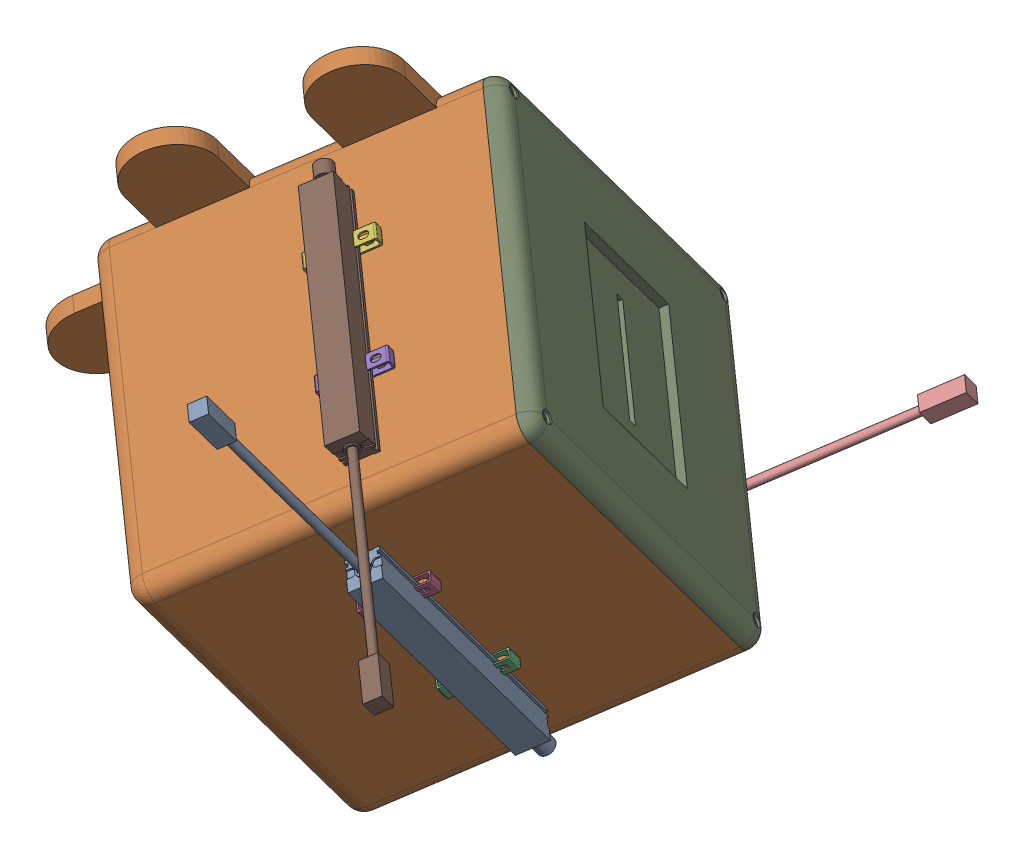
SolidWorks assembly CajaCompleta, configuration Predeterminado. Lengths in mm.
Overall size (364.03 428.6 429.87).
11 component instances, 4 part files, 30 mates.
Components (placement in the parent):
- Sensor-1: Sensor [Predeterminado] at (-9.7857 -175.398 154.3753) x (-0.665785 -0.507971 0.546532) z (-0.153398 0.810013 0.565993) size (17.8 17.82 298.41)
- Servicio-1: Servicio [Predeterminado] at (-86.6429 -170.5093 84.1469) x (-0.730205 0.292992 -0.617216) z (-0.153398 0.810013 0.565993) size (200 250 300)
- soporteSensor-1: soporteSensor [Predeterminado] at (-10.5547 -140.3431 170.4675) x (-0.665785 -0.507971 0.546532) z (-0.153398 0.810013 0.565993) size (37.6 6.1 8.9)
- soporteSensor-2: soporteSensor [Predeterminado] at (-20.9676 -85.3782 208.8785) x (-0.665785 -0.507971 0.546532) z (-0.153398 0.810013 0.565993) size (37.6 6.1 8.9)
- soporteSensor-3: soporteSensor [Predeterminado] at (-91.6649 -13.9921 212.1498) x (0.665785 0.507971 -0.546532) z (0.730205 -0.292992 0.617216) size (37.6 6.1 8.9)
- soporteSensor-4: soporteSensor [Predeterminado] at (-141.2166 5.8903 170.2655) x (0.665785 0.507971 -0.546532) z (0.730205 -0.292992 0.617216) size (37.6 6.1 8.9)
- soporteSensor-5: soporteSensor [Predeterminado] at (-47.3623 -156.5216 74.7747) x (-0.730205 0.292992 -0.617216) z (-0.665785 -0.507971 0.546532) size (37.6 6.1 8.9)
- soporteSensor-6: soporteSensor [Predeterminado] at (-92.5406 -190.9932 111.8639) x (-0.730205 0.292992 -0.617216) z (-0.665785 -0.507971 0.546532) size (37.6 6.1 8.9)
- Servicio_tapa-1: Servicio_tapa [Predeterminado] at (-35.4043 -38.7109 86.093) x (0.153398 -0.810013 -0.565993) z (0.665785 0.507971 -0.546532) size (200 200 10)
- Sensor-2: Sensor [Predeterminado] at (-140.7801 -203.8923 115.6599) x (0.730205 -0.292992 0.617216) z (0.665785 0.507971 -0.546532) size (17.8 17.82 298.41)
- Sensor-3: Sensor [Predeterminado] at (-154.1478 18.341 150.5324) x (0.665785 0.507971 -0.546532) z (0.730205 -0.292992 0.617216) size (17.8 17.82 298.41)
Mates (geometry in assembly coordinates):
- Coincidente1: coincident anti-aligned: plane of Servicio-1 through (22.2765 12.9912 204.4139) normal (0.730205 -0.292992 0.617216); plane of soporteSensor-1 through (-11.9199 -133.134 175.5048) normal (-0.730205 0.292992 -0.617216)
- Concéntrica1: concentric aligned: cylinder of Servicio-1 through (-15.9467 -140.378 176.83) axis (0.730205 -0.292992 0.617216) radius 2; cylinder of soporteSensor-1 through (-9.4479 -142.9857 182.3232) axis (0.730205 -0.292992 0.617216) radius 2
- Coincidente3: coincident anti-aligned: plane of Servicio-1 through (22.2765 12.9912 204.4139) normal (0.730205 -0.292992 0.617216); plane of soporteSensor-2 through (-22.3329 -78.1691 213.9158) normal (-0.730205 0.292992 -0.617216)
- Concéntrica2: concentric aligned: cylinder of Servicio-1 through (-26.375 -85.3321 215.2976) axis (0.730205 -0.292992 0.617216) radius 2; cylinder of soporteSensor-2 through (-19.8762 -87.9397 220.7908) axis (0.730205 -0.292992 0.617216) radius 2
- Coincidente4: coincident anti-aligned: plane of Servicio-1 through (-86.6429 -170.5093 84.1469) normal (0.153398 -0.810013 -0.565993); plane of soporteSensor-6 through (-98.4661 -195.5142 116.728) normal (-0.153398 0.810013 0.565993)
- Coincidente5: coincident anti-aligned: plane of Servicio-1 through (-86.6429 -170.5093 84.1469) normal (0.153398 -0.810013 -0.565993); plane of soporteSensor-5 through (-53.2877 -161.0426 79.6388) normal (-0.153398 0.810013 0.565993)
- Concéntrica3: concentric aligned: cylinder of Servicio-1 through (-55.9039 -149.0202 79.3922) axis (0.153398 -0.810013 -0.565993) radius 2; cylinder of soporteSensor-5 through (-53.0047 -164.3294 68.695) axis (0.153398 -0.810013 -0.565993) radius 2
- Concéntrica4: concentric aligned: cylinder of Servicio-1 through (-101.0822 -183.4918 116.4814) axis (0.153398 -0.810013 -0.565993) radius 2; cylinder of soporteSensor-6 through (-98.183 -198.8011 105.7841) axis (0.153398 -0.810013 -0.565993) radius 2
- Coincidente6: coincident anti-aligned: plane of Servicio-1 through (-117.3225 -8.5067 197.3455) normal (-0.153398 0.810013 0.565993); plane of soporteSensor-3 through (-85.1661 -16.5997 217.643) normal (0.153398 -0.810013 -0.565993)
- Coincidente7: coincident anti-aligned: plane of Servicio-1 through (-117.3225 -8.5067 197.3455) normal (-0.153398 0.810013 0.565993); plane of soporteSensor-4 through (-134.7178 3.2827 175.7587) normal (0.153398 -0.810013 -0.565993)
- Coincidente9: coincident anti-aligned: plane of Sensor-1 through (-31.8014 -59.1449 235.6066) normal (-0.730205 0.292992 -0.617216); plane of soporteSensor-2 through (-20.3104 -85.6419 209.434) normal (0.730205 -0.292992 0.617216)
- Coincidente10: coincident anti-aligned: plane of Servicio-1 through (22.2765 12.9912 204.4139) normal (0.665785 0.507971 -0.546532); plane of Servicio_tapa-1 through (-35.4043 -38.7109 86.093) normal (-0.665785 -0.507971 0.546532)
- Coincidente11: coincident aligned: line of Servicio-1 through (-42.2658 -95.6948 229.1782) axis (-0.665785 -0.507971 0.546532); line of soporteSensor-2 through (-42.2658 -95.6948 229.1782) axis (-0.665785 -0.507971 0.546532)
- Coincidente12: coincident aligned: line of Servicio-1 through (-31.8595 -150.6648 190.7727) axis (-0.665785 -0.507971 0.546532); line of soporteSensor-1 through (-31.8529 -150.6598 190.7672) axis (-0.665785 -0.507971 0.546532)
- Coincidente13: coincident anti-aligned: circle of Servicio-1; circle of Servicio_tapa-1
- Coincidente14: coincident anti-aligned: circle of Servicio-1; circle of Servicio_tapa-1
- Coincidente21: coincident anti-aligned: circle of Servicio-1; circle of soporteSensor-5
- Coincidente41: coincident anti-aligned: line of Servicio-1 through (-116.4891 -183.3218 94.3943) axis (-0.730205 0.292992 -0.617216); line of soporteSensor-6 through (-117.5826 -182.883 93.47) axis (0.730205 -0.292992 0.617216)
- Coincidente44: coincident anti-aligned: plane of Sensor-1 through (-31.8014 -59.1449 235.6066) normal (-0.730205 0.292992 -0.617216); plane of soporteSensor-1 through (-9.8975 -140.6068 171.023) normal (0.730205 -0.292992 0.617216)
- Coincidente45: coincident anti-aligned: plane of Sensor-1 through (-43.6524 -68.1868 245.3349) normal (-0.665785 -0.507971 0.546532); plane of soporteSensor-1 through (-28.0648 -153.7027 184.8412) normal (0.665785 0.507971 -0.546532)
- Coincidente46: coincident anti-aligned: plane of soporteSensor-5 through (-47.2242 -157.2506 74.2653) normal (0.153398 -0.810013 -0.565993); plane of Sensor-2 through (-45.2267 -130.9883 37.2217) normal (-0.153398 0.810013 0.565993)
- Coincidente47: coincident anti-aligned: plane of soporteSensor-6 through (-92.4025 -191.7223 111.3545) normal (0.153398 -0.810013 -0.565993); plane of Sensor-2 through (-45.2267 -130.9883 37.2217) normal (-0.153398 0.810013 0.565993)
- Coincidente48: coincident anti-aligned: plane of soporteSensor-5 through (-55.6136 -153.2108 67.8002) normal (-0.730205 0.292992 -0.617216); plane of Sensor-2 through (-32.2291 -136.2036 48.2081) normal (0.730205 -0.292992 0.617216)
- Concéntrica15: concentric anti-aligned: circle of Servicio-1; circle of soporteSensor-4
- Coincidente50: coincident anti-aligned: circle of Servicio-1; circle of soporteSensor-3
- Coincidente51: coincident anti-aligned: line of Servicio-1 through (-131.8329 7.6091 170.349) axis (-0.665785 -0.507971 0.546532); line of soporteSensor-4 through (-132.8249 6.8522 171.1633) axis (0.665785 0.507971 -0.546532)
- Coincidente52: coincident anti-aligned: line of Servicio-1 through (-82.2812 -12.2734 212.2332) axis (-0.665785 -0.507971 0.546532); line of soporteSensor-3 through (-83.2732 -13.0302 213.0476) axis (0.665785 0.507971 -0.546532)
- Coincidente53: coincident anti-aligned: plane of soporteSensor-3 through (-91.803 -13.2631 212.6592) normal (-0.153398 0.810013 0.565993); plane of Sensor-3 through (-49.3487 -23.7093 239.1152) normal (0.153398 -0.810013 -0.565993)
- Coincidente54: coincident anti-aligned: plane of soporteSensor-4 through (-141.3547 6.6194 170.7749) normal (-0.153398 0.810013 0.565993); plane of Sensor-3 through (-49.3487 -23.7093 239.1152) normal (0.153398 -0.810013 -0.565993)
- Coincidente55: coincident anti-aligned: plane of soporteSensor-3 through (-74.1548 -0.6325 197.776) normal (-0.665785 -0.507971 0.546532); plane of Sensor-3 through (-37.4977 -14.6674 229.3869) normal (0.665785 0.507971 -0.546532)
